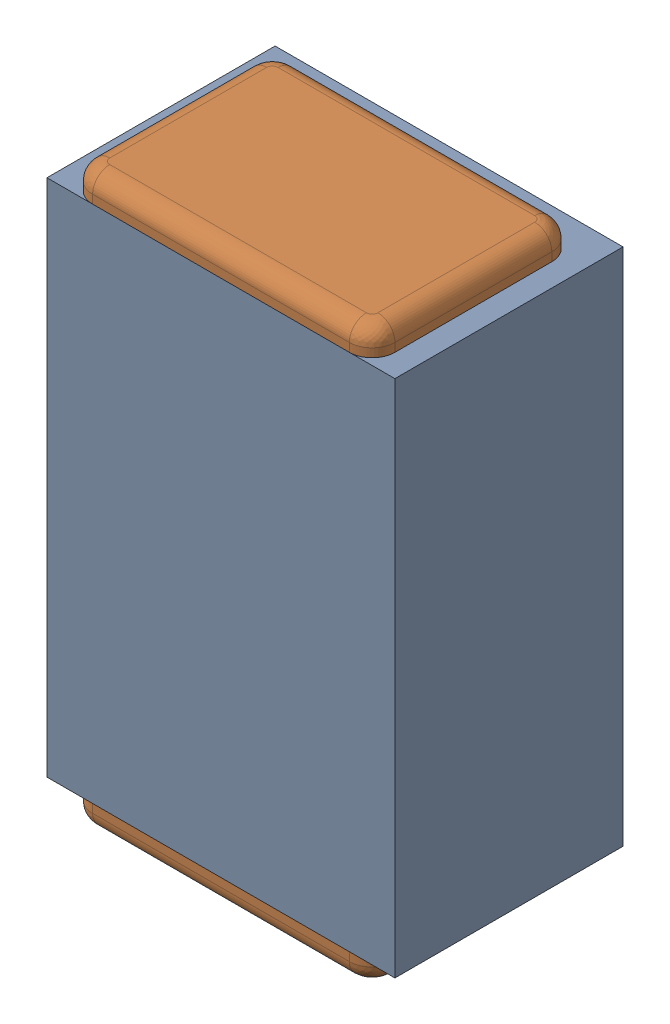
SolidWorks assembly C29, configuration Default. Lengths in mm.
Overall size (0.61 1 0.4).
3 component instances, 2 part files, 0 mates.
Components (placement in the parent):
- 1088881848-1: 1088881848 [Default] at (12.775 31.775 -2.044) size (0.61 0.91 0.4)
  - Extruded-1-1: Extruded-1 [Default] at origin size (0.61 0.91 0.4)
- C0402-1: C0402 [Default] at (12.7751 31.7751 -1.644) x (0 1 0) z (-1 0 0) size (1 0.36 0.54)
